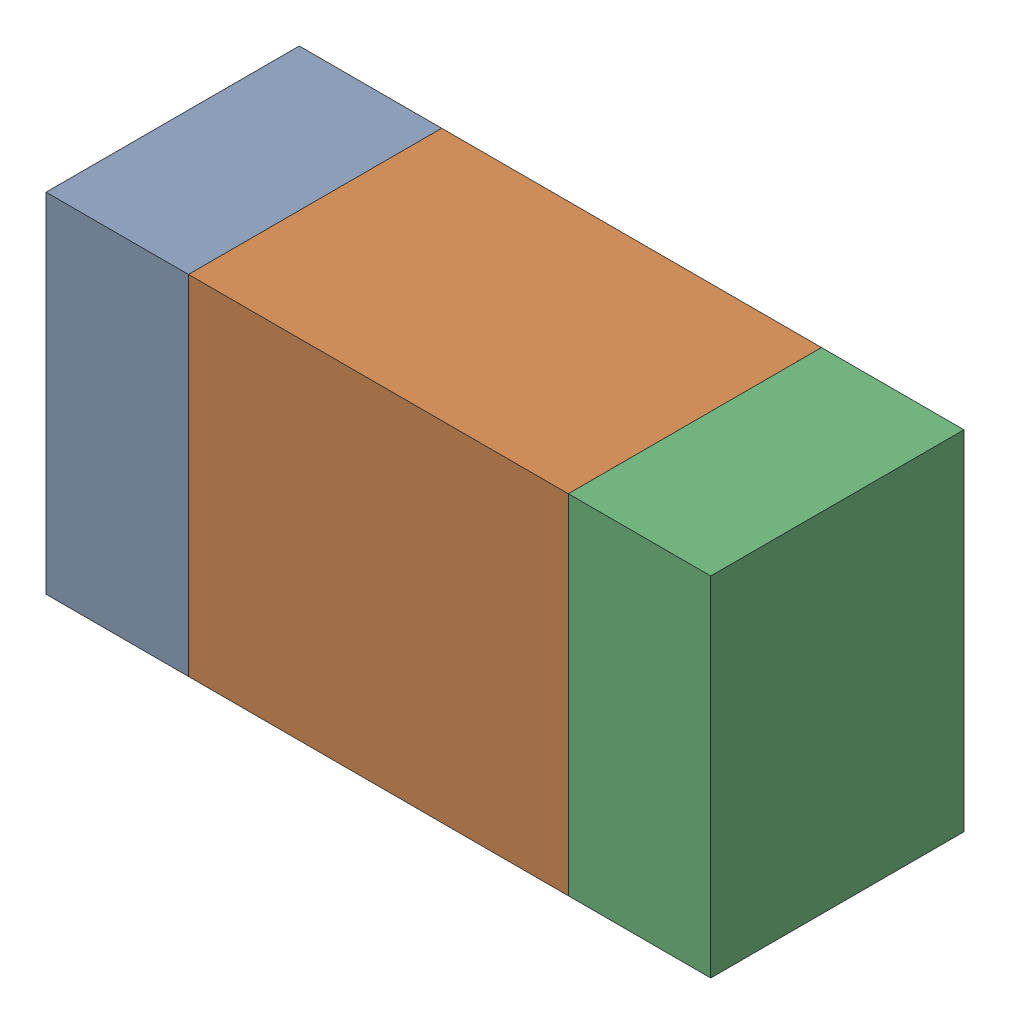
SolidWorks assembly R500_2PCB, configuration Default. Lengths in mm.
Overall size (1.05 0.55 0.4).
6 component instances, 2 part files, 0 mates.
Components (placement in the parent):
- 854785432-1: 854785432 [Default] at (156.0628 90.2681 0) size (0.22 0.55 0.4)
  - Extruded-1: Extruded [Default] at origin size (0.22 0.55 0.4)
- 854785568-1: 854785568 [Default] at (156.4753 90.2681 0) size (0.6 0.55 0.4)
  - Extruded_2-1: Extruded_2 [Default] at origin size (0.6 0.55 0.4)
- 854785432-2: 854785432 [Default] at (156.8878 90.2681 0) size (0.22 0.55 0.4)
  - Extruded-1: Extruded [Default] at origin size (0.22 0.55 0.4)
